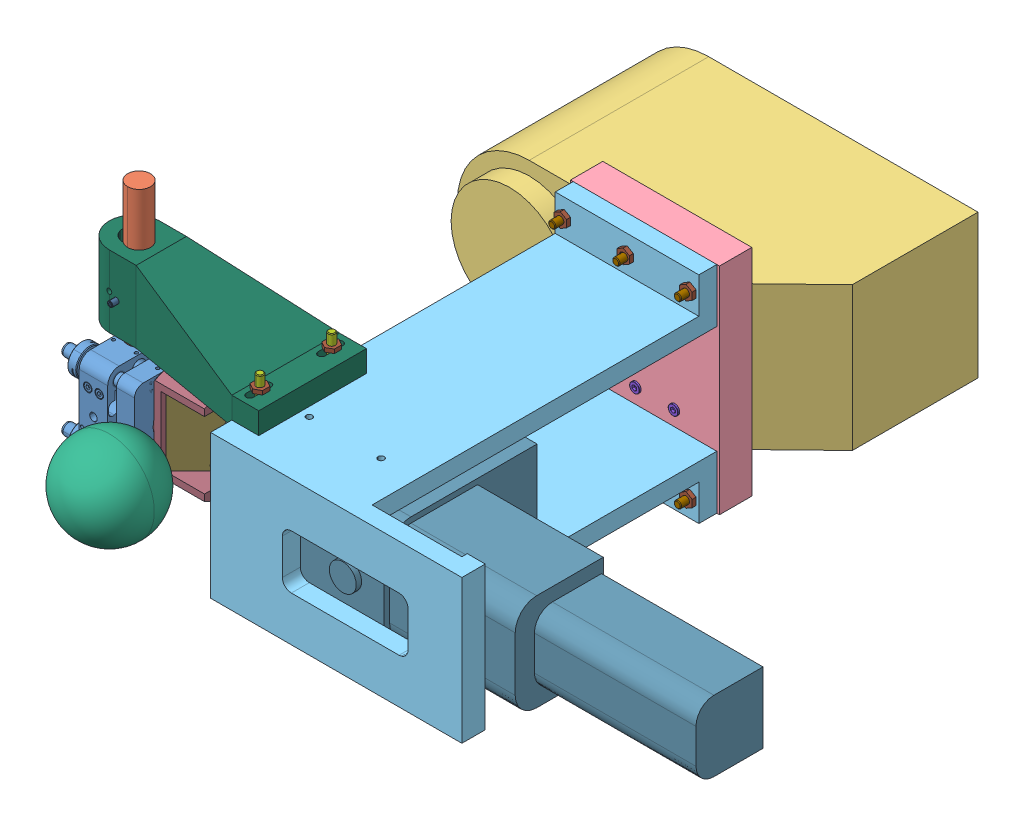
SolidWorks assembly Assemble04, configuration Default. Lengths in mm.
Overall size (348.17 161.32 358.85).
46 component instances, 21 part files, 11 mates.
Components (placement in the parent):
- Assemble02.STEP-1: Assemble02.STEP [Default] at origin size (349.27 161.32 358.85)
  - Mirror_Asm.STEP-1: Mirror_Asm.STEP [Default] at (85.4732 -9.4624 459.1976) x (0 0 -1) z (-1 0 0) size (53.98 128.56 72.15)
    - LightSplitter.STEP-1: LightSplitter.STEP [Default] at (20.4935 15.8139 165.2643) x (0 0 -1) z (0 1 0) size (25 25 25)
      - LightSplitter.stp.STEP-1: LightSplitter.stp.STEP [Default] at origin size (25 25 25) (hidden)
        - _LightSplitter.stp.STEP-1: _LightSplitter.stp.STEP [Default] at (11.341 43.5459 -25.6775) x (-1 0 0) z (0 0 1) size (25 25 25)
        - _LightSplitter.stp.STEP-2: _LightSplitter.stp.STEP [Default] at (-13.659 18.5459 -25.6775) size (25 25 25)
    - Newport-U100-A3H.STEP-1: Newport-U100-A3H.STEP [Default] at (-104.4188 -96.9377 53.975) size (53.98 53.98 42.58)
    - Newport-UPA-CH1.STEP-1: Newport-UPA-CH1.STEP [Default] at (-10.3524 -11.9773 189.0833) x (0 1 0) z (0 0 -1) size (40.85 25.4 35.56) (hidden)
    - Mirror_Bar.STEP-1: Mirror_Bar.STEP [Default] at (-10.3524 -98.6828 204.4218) x (1 0 0) z (0 1 0) size (12.68 12.68 76.17)
  - Microscope.STEP-1: Microscope.STEP [Default] at (68.8214 -52.0988 190) size (190 80 111)
  - MicroscopeConnector.STEP-1: MicroscopeConnector.STEP [Default] at (34.8214 -38.3488 293) x (0 1 0) z (0 0 1) size (120 83 18)
  - OCT2.STEP-1: OCT2.STEP [Default] at (-20.9301 18.0012 414.75) x (0 0 1) z (1 0 0) size (88.25 60.2 267.12) (hidden)
  - OCT_holder2_2.STEP-1: OCT_holder2_2.STEP [Default] at (-38.6786 27.9012 510) x (1 0 0) z (0 0 -1) size (140 120 202)
  - PigEye.STEP-1: PigEye.STEP [Default] at (-81.1786 -12.0988 548.85) x (0.90772 0.419577 0) z (-0.419577 0.90772 0) size (50 48 50)
  - Mirror_holder.STEP-1: Mirror_holder.STEP [Default] at (-118.9486 17.4012 469.55) x (1 0 0) z (0 1 0) size (109.27 60 40) (hidden)
  - socket head cap screw_iso_ISO 4762 M4 x 30 - 20C.STEP-1: socket head cap screw_iso_ISO 4762 M4 x 30 - 20C.STEP [Default] at (-33.6786 14.0012 447.5) x (0 1 0) z (0 0 1) size (34 7 7)
  - socket head cap screw_iso_ISO 4762 M4 x 30 - 20C.STEP-2: socket head cap screw_iso_ISO 4762 M4 x 30 - 20C.STEP [Default] at (-33.6786 14.0012 487.5) x (0 1 0) z (0 0 1) size (34 7 7)
  - socket head cap screw_iso_ISO 4762 M3 x 20 - 20C.STEP-1: socket head cap screw_iso_ISO 4762 M3 x 20 - 20C.STEP [Default] at (-3.5786 -33.5988 309) x (0 0 -1) z (1 0 0) size (23 5.5 5.5)
  - socket head cap screw_iso_ISO 4762 M3 x 20 - 20C.STEP-2: socket head cap screw_iso_ISO 4762 M3 x 20 - 20C.STEP [Default] at (17.9214 -33.5988 309) x (0 0 -1) z (1 0 0) size (23 5.5 5.5)
  - socket head cap screw_iso_ISO 4762 M3 x 20 - 20C.STEP-3: socket head cap screw_iso_ISO 4762 M3 x 20 - 20C.STEP [Default] at (-3.5786 9.4012 309) x (0 0 -1) z (1 0 0) size (23 5.5 5.5)
  - socket head cap screw_iso_ISO 4762 M3 x 20 - 20C.STEP-4: socket head cap screw_iso_ISO 4762 M3 x 20 - 20C.STEP [Default] at (17.9214 9.4012 309) x (0 0 -1) z (1 0 0) size (23 5.5 5.5)
  - hex bolt gradeb_iso_ISO 4015 - M4 x 30 x 30-C.STEP-1: hex bolt gradeb_iso_ISO 4015 - M4 x 30 x 30-C.STEP [Default] at (-33.6786 37.9012 292.2) x (0 0 1) z (-1 0 0) size (32.81 8.1 8.09)
  - hex bolt gradeb_iso_ISO 4015 - M4 x 30 x 30-C.STEP-2: hex bolt gradeb_iso_ISO 4015 - M4 x 30 x 30-C.STEP [Default] at (36.3214 37.9012 292.2) x (0 0 1) z (-1 0 0) size (32.81 8.1 8.09)
  - hex bolt gradeb_iso_ISO 4015 - M4 x 30 x 30-C.STEP-3: hex bolt gradeb_iso_ISO 4015 - M4 x 30 x 30-C.STEP [Default] at (2.0049 37.9012 292.2) x (0 0 1) z (-1 0 0) size (32.81 8.1 8.09)
  - hex bolt gradeb_iso_ISO 4015 - M4 x 30 x 30-C.STEP-4: hex bolt gradeb_iso_ISO 4015 - M4 x 30 x 30-C.STEP [Default] at (36.3214 -62.0988 292.2) x (0 0 1) z (-1 0 0) size (32.81 8.1 8.09)
  - hex bolt gradeb_iso_ISO 4015 - M4 x 30 x 30-C.STEP-5: hex bolt gradeb_iso_ISO 4015 - M4 x 30 x 30-C.STEP [Default] at (1.3214 -62.0988 292.2) x (0 0 1) z (-1 0 0) size (32.81 8.1 8.09)
  - hex bolt gradeb_iso_ISO 4015 - M4 x 30 x 30-C.STEP-6: hex bolt gradeb_iso_ISO 4015 - M4 x 30 x 30-C.STEP [Default] at (-33.6786 -62.0988 292.2) x (0 0 1) z (-1 0 0) size (32.81 8.1 8.09)
  - socket set screw cone point_iso_ISO 4027 - M3 x 8-N.STEP-1: socket set screw cone point_iso_ISO 4027 - M3 x 8-N.STEP [Default] at (-118.9486 37.4012 452.5076) x (0 0 1) z (-0.367036 0.930207 0) size (8 3 3)
  - socket set screw cone point_iso_ISO 4027 - M3 x 8-N.STEP-2: socket set screw cone point_iso_ISO 4027 - M3 x 8-N.STEP [Default] at (-118.9486 37.4012 485.8038) x (0 0 -1) z (0.477067 -0.878867 0) size (8 3 3)
  - hex thin nut gradeb_iso_ISO - 4036 - M4 - C.STEP-1: hex thin nut gradeb_iso_ISO - 4036 - M4 - C.STEP [Default] at (-33.6786 37.9012 320.2) size (7 8.08 2.2)
  - hex thin nut gradeb_iso_ISO - 4036 - M4 - C.STEP-2: hex thin nut gradeb_iso_ISO - 4036 - M4 - C.STEP [Default] at (1.3214 37.9012 320.2) size (7 8.08 2.2)
  - hex thin nut gradeb_iso_ISO - 4036 - M4 - C.STEP-3: hex thin nut gradeb_iso_ISO - 4036 - M4 - C.STEP [Default] at (36.3214 37.9012 320.2) size (7 8.08 2.2)
  - hex thin nut gradeb_iso_ISO - 4036 - M4 - C.STEP-4: hex thin nut gradeb_iso_ISO - 4036 - M4 - C.STEP [Default] at (36.3214 -62.0988 320.2) size (7 8.08 2.2)
  - hex thin nut gradeb_iso_ISO - 4036 - M4 - C.STEP-5: hex thin nut gradeb_iso_ISO - 4036 - M4 - C.STEP [Default] at (1.3214 -62.0988 320.2) size (7 8.08 2.2)
  - hex thin nut gradeb_iso_ISO - 4036 - M4 - C.STEP-6: hex thin nut gradeb_iso_ISO - 4036 - M4 - C.STEP [Default] at (-33.6786 -62.0988 320.2) size (7 8.08 2.2)
  - hex thin nut gradeb_iso_ISO - 4036 - M4 - C.STEP-7: hex thin nut gradeb_iso_ISO - 4036 - M4 - C.STEP [Default] at (-33.6786 39.9012 447.5) x (1 0 0) z (0 -1 0) size (7 8.08 2.2)
  - hex thin nut gradeb_iso_ISO - 4036 - M4 - C.STEP-8: hex thin nut gradeb_iso_ISO - 4036 - M4 - C.STEP [Default] at (-33.6786 39.9012 487.5) x (1 0 0) z (0 -1 0) size (7 8.08 2.2)
- LenseFixture4-1: LenseFixture4 [Default] at (-102.2683 39.8547 452.8616) x (0 1 0) z (1 0 0) size (40.79 30.48 40.64) (hidden)
  - Newport-UPA-CH1_5-1: Newport-UPA-CH1_5 [預設] at (-67.0687 16.6884 -1.5704) size (40.79 30.48 40.64)
  - Lense1-1: Lense1 [Default] at (-65.4122 30.5849 9.9331) x (0 -0.707107 0.707107) z (0 0.707107 0.707107) size (38 26 1)
- LenseFixture3-1: LenseFixture3 [Default] at (-98.7984 40.0212 448.8436) x (0 1 0) z (1 0 0) size (51.67 25.91 34.29)
  - Lense1-1: Lense1 [Default] at (-33.1938 32.3169 6.4632) x (-1 0 0) z (0 0.707107 0.707107) size (38 26 1)
  - Newport-UPA-CH1_4-1: Newport-UPA-CH1_4 [預設] at (-67.2353 20.7064 -5.0403) size (51.67 25.91 34.29)
- OCT3-1: OCT3 [預設] at (-22.0244 18.0012 414.75) x (0 0 1) z (1 0 0) size (88.25 60.2 267.12)
- OCT_holder3_2-1: OCT_holder3_2 [預設] at (-140.6404 155.1398 354.9518) size (140 120 202) (hidden)
- Mirror_holder2-1: Mirror_holder2 [預設] at (-122.9486 19.9012 468.1575) x (1 0 0) z (0 1 0) size (113.27 60 40)
Mates (geometry in assembly coordinates):
- Concentric1: concentric anti-aligned: cylinder of Assemble02.STEP-1/Mirror_Asm.STEP-1/Newport-U100-A3H.STEP-1 through (-107.6487 -12.3496 469.55) axis (1 0 0) radius 11.684; cylinder of LenseFixture4-1/Newport-UPA-CH1_5-1 through (-97.6157 -12.3496 469.55) axis (-1 0 0) radius 12.7
- Coincident1: coincident anti-aligned: plane of Assemble02.STEP-1/Mirror_Asm.STEP-1/Newport-U100-A3H.STEP-1 through (-97.6157 11.5264 493.426) normal (1 0 0); plane of LenseFixture4-1/Newport-UPA-CH1_5-1 through (-97.6157 -12.3496 469.55) normal (-1 0 0)
- Parallel1: parallel anti-aligned: plane of Assemble02.STEP-1/OCT_holder2_2.STEP-1 through (31.3214 -12.0988 510) normal (0 0 1); plane of LenseFixture4-1/Newport-UPA-CH1_5-1 through (-129.6362 -27.2141 454.31) normal (0 0 -1)
- Concentric2: concentric anti-aligned: cylinder of Assemble02.STEP-1/Mirror_Asm.STEP-1/Newport-U100-A3H.STEP-1 through (-107.6487 -12.3496 469.55) axis (1 0 0) radius 11.684; cylinder of LenseFixture3-1/Newport-UPA-CH1_4-1 through (-97.6157 -12.3496 469.55) axis (-1 0 0) radius 12.7
- Coincident3: coincident anti-aligned: plane of Assemble02.STEP-1/Mirror_Asm.STEP-1/Newport-U100-A3H.STEP-1 through (-97.6157 11.5264 493.426) normal (1 0 0); plane of LenseFixture3-1/Newport-UPA-CH1_4-1 through (-97.6157 -12.3496 469.55) normal (-1 0 0)
- Parallel2: parallel anti-aligned: plane of Assemble02.STEP-1/OCT_holder2_2.STEP-1 through (31.3214 -12.0988 510) normal (0 0 1); plane of LenseFixture3-1/Newport-UPA-CH1_4-1 through (-142.6164 -27.2141 456.596) normal (0 0 -1)
- 重合/共線/共點1: coincident anti-aligned: plane of Assemble02.STEP-1/OCT_holder2_2.STEP-1 through (31.3214 -12.0988 500) normal (0 0 -1); plane of OCT3-1 through (-22.0244 3.0012 500) normal (0 0 1)
- 平行1: parallel anti-aligned: plane of Assemble02.STEP-1/OCT_holder2_2.STEP-1 through (-38.6786 -52.0988 510) normal (-1 0 0); plane of OCT3-1 through (47.9756 -12.0988 457.375) normal (1 0 0)
- 重合/共線/共點3: coincident anti-aligned: plane of Assemble02.STEP-1/OCT_holder2_2.STEP-1 through (-38.6786 -42.1988 500) normal (0 1 0); plane of OCT3-1 through (-22.0244 -42.1988 485) normal (0 -1 0)
- 重合/共線/共點4: coincident anti-aligned: plane of Assemble02.STEP-1/OCT_holder2_2.STEP-1 through (-38.6786 27.9012 510) normal (0 1 0); plane of Mirror_holder2-1 through (-23.6786 27.9012 438.1575) normal (0 -1 0)
- 重合/共線/共點5: coincident anti-aligned: plane of Assemble02.STEP-1/OCT_holder2_2.STEP-1 through (-38.6786 -52.0988 510) normal (-1 0 0); plane of Mirror_holder2-1 through (-38.6786 19.9012 468.1575) normal (1 0 0)
